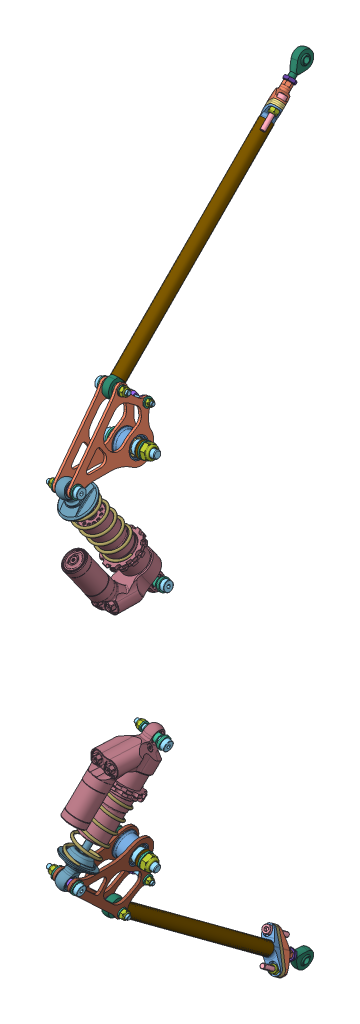
SolidWorks assembly PUTM-S-SR-DS, configuration Domyślna. Lengths in mm.
Overall size (128 1101.89 413.23).
117 component instances, 24 part files, 8 mates.
Components (placement in the parent):
- PUTM-S-SR-DS-Rocker-1: PUTM-S-SR-DS-Rocker [Domyślna] at origin size (72.21 637.68 125.56)
  - PUTM_S_SR_DS_Rockersleeve-1: PUTM_S_SR_DS_Rockersleeve [Domyślna] at (-1449.4181 239.4336 437.1843) x (0.986079 0.166257 -0.00253) z (0.063822 -0.364394 0.929055) size (24 33 33)
  - PUTM-S-SR-DS-Rockerplate-1: PUTM-S-SR-DS-Rockerplate [Domyślna] at (8.972 14.8477 31.7784) x (0.999705 0.009752 0.022243) z (-0.022218 -0.002628 0.99975) size (19.82 96.34 120.76)
  - PUTM-S-SR-DS-Rockerplate-2: PUTM-S-SR-DS-Rockerplate [Domyślna] at (-11.2426 11.4394 31.8303) x (0.999705 0.009752 0.022243) z (-0.022218 -0.002628 0.99975) size (19.82 96.34 120.76)
  - PUTM-S-SR-DS-NKIB 5901-1: PUTM-S-SR-DS-NKIB 5901 [Domyślna] at (-1457.4053 238.0869 437.2048) x (0.986079 0.166257 -0.00253) z (-0.069911 0.428358 0.900901) size (17.5 24 24)
  - PUTM-S-SR-DS-Seger-1: PUTM-S-SR-DS-Seger [24 mm] at (-1457.4053 238.0869 437.2048) x (0.038864 -0.215655 0.975696) z (-0.986079 -0.166257 0.00253) size (25.2 25.11 1.2)
  - PUTM-FT-ELESA_ISO7379-1: PUTM-FT-ELESA_ISO7379 [8-M6-25] at (-1479.6872 304.2624 449.2226) x (-0.986079 -0.166257 0.00253) z (0.161473 -0.961118 -0.224006) size (41.5 13 13)
  - PUTM-FT-FABORY_ISO7089-1: PUTM-FT-FABORY_ISO7089 [M8 [38093.080.001]] at (-1472.686 305.4428 449.2046) x (0.028434 -0.153611 0.987722) z (-0.986079 -0.166257 0.00253) size (16 16 1.6)
  - PUTM-FT-FABORY_ISO7089-2: PUTM-FT-FABORY_ISO7089 [M6 [38093.060.001]] at (-1447.4424 309.699 449.1398) x (0.032173 -0.175846 0.983892) z (-0.986079 -0.166257 0.00253) size (12 12 1.6)
  - PUTM-FT-FABORY_DIN985-1: PUTM-FT-FABORY_DIN985 [M6 [12348.060.001]] at (-1447.4424 309.699 449.1398) x (0.058443 -0.360799 -0.930811) z (0.986079 0.166257 -0.00253) size (11.9 10.35 6.18)
  - PUTM-FT-ELESA_ISO7379-2: PUTM-FT-ELESA_ISO7379 [6-M5-25] at (-1474.3165 277.9597 418.7611) x (-0.986079 -0.166257 0.00253) z (0.008863 -0.037361 0.999263) size (39 10 10)
  - PUTM-FT-FABORY_ISO7089-3: PUTM-FT-FABORY_ISO7089 [M6 [38093.060.001]] at (-1469.8791 278.7078 418.7497) x (0.116001 -0.676949 0.726831) z (0.986079 0.166257 -0.00253) size (12 12 1.6)
  - PUTM-FT-FABORY_ISO7089-4: PUTM-FT-FABORY_ISO7089 [M6 [38093.060.001]] at (-1443.0578 283.23 418.6809) x (0.028501 -0.15401 0.987658) z (-0.986079 -0.166257 0.00253) size (12 12 1.6)
  - PUTM-FT-FABORY_DIN985-2: PUTM-FT-FABORY_DIN985 [M5 [12348.050.001]] at (-1443.0578 283.23 418.6809) x (0.063056 -0.387983 -0.919507) z (0.986079 0.166257 -0.00253) size (9.51 8.27 5.13)
  - PUTM-FT-ELESA_ISO7379-3: PUTM-FT-ELESA_ISO7379 [8-M6-30] at (-1427.6768 235.7327 525.4287) x (0.986079 0.166257 -0.00253) z (0.154521 -0.921884 -0.355322) size (46.5 13 13)
  - PUTM-FT-FABORY_ISO7089-5: PUTM-FT-FABORY_ISO7089 [M8 [38093.080.001]] at (-1433.1002 234.8183 525.4426) x (0.058573 -0.36156 -0.930507) z (-0.986079 -0.166257 0.00253) size (16 16 1.6)
  - PUTM-FT-FABORY_ISO7089-6: PUTM-FT-FABORY_ISO7089 [M6 [38093.060.001]] at (-1461.4007 230.0467 525.5152) x (0.066136 -0.406128 -0.91142) z (-0.986079 -0.166257 0.00253) size (12 12 1.6)
  - PUTM-FT-FABORY_DIN985-3: PUTM-FT-FABORY_DIN985 [M6 [12348.060.001]] at (-1462.9785 229.7807 525.5193) x (-0.080848 0.492701 0.866435) z (-0.986079 -0.166257 0.00253) size (11.9 10.35 6.18)
  - PUTM-FT-ELESA_ISO7379-7: PUTM-FT-ELESA_ISO7379 [12-M10-45] at (-1479.9865 234.2796 437.2628) x (-0.986079 -0.166257 0.00253) z (0.136222 -0.816481 -0.561073) size (69 18 18)
  - PUTM-FT-FABORY_ISO7089-13: PUTM-FT-FABORY_ISO7089 [M12 [38093.120.001]] at (-1472.0979 235.6097 437.2425) x (0.070497 -0.431808 -0.899206) z (0.986079 0.166257 -0.00253) size (24 24 2.5)
  - PUTM-FT-FABORY_ISO7089-14: PUTM-FT-FABORY_ISO7089 [M10 [38093.100.001]] at (-1427.2313 243.1743 437.1274) x (0.028505 -0.154033 0.987654) z (-0.986079 -0.166257 0.00253) size (20 20 2)
  - PUTM-FT-FABORY_DIN985-7: PUTM-FT-FABORY_DIN985 [M10 [12348.100.001]] at (-1427.2313 243.1743 437.1274) x (0.063056 -0.387983 -0.919507) z (0.986079 0.166257 -0.00253) size (20.27 17.64 10.37)
  - PUTM-FT-FABORY_ISO7089-17: PUTM-FT-FABORY_ISO7089 [M8 [38093.080.001]] at (-1459.823 230.3127 525.5112) x (0.030102 -0.163528 0.986079) z (-0.986079 -0.166257 0.00253) size (16 16 1.6)
  - PUTM-S-Mush-1: PUTM-S-Mush [8x2] at (-1469.2348 306.0247 449.1958) x (0.986079 0.166257 -0.00253) z (-0.00325 0.034487 0.9994) size (2 12 12)
  - PUTM-S-Mush-2: PUTM-S-Mush [8x2] at (-1452.4714 308.8511 449.1527) x (-0.986079 -0.166257 0.00253) z (0.161903 -0.956569 0.24241) size (2 12 12)
  - PUTM-S-Mush-3: PUTM-S-Mush [6x4.5] at (-1464.8501 279.5557 418.7368) x (0.986079 0.166257 -0.00253) z (-0.012976 0.092116 0.995664) size (4.5 12 12)
  - PUTM-S-Mush-4: PUTM-S-Mush [6x4.5] at (-1448.0868 282.3821 418.6938) x (-0.986079 -0.166257 0.00253) z (0.038498 -0.243087 -0.96924) size (4.5 12 12)
  - PUTM-S-Mush-5: PUTM-S-Mush [6x5] at (-1456.3717 230.8946 525.5023) x (0.986079 0.166257 -0.00253) z (0.000139 0.014393 0.999896) size (4.5 12 12)
  - PUTM-S-Mush-6: PUTM-S-Mush [6x5] at (-1439.6084 233.721 525.4593) x (-0.986079 -0.166257 0.00253) z (0.038498 -0.243087 -0.96924) size (4.5 12 12)
  - PUTM-S-SR-Rocker-MushRocker-1: PUTM-S-SR-Rocker-MushRocker [Domyślna] at (-1432.2603 242.3264 437.1403) x (-0.986079 -0.166257 0.00253) z (0.11055 -0.666893 -0.736907) size (8 20 20)
  - PUTM-S-SR-Rocker-MushRocker_long-1: PUTM-S-SR-Rocker-MushRocker_long [Domyślna] at (-1466.7731 236.5075 437.2289) x (0.986079 0.166257 -0.00253) z (0.00253 0.000212 0.999997) size (9.5 20 20)
  - PUTM-FT-FABORY_ISO7089-7: PUTM-FT-FABORY_ISO7089 [M6 [38093.060.001]] at (-1449.0201 -309.433 449.1439) x (0.032173 0.175846 0.983892) z (0.986079 -0.166257 -0.00253) size (12 12 1.6)
  - PUTM-S-Mush-7: PUTM-S-Mush [6x4.5] at (-1448.0868 -282.3821 418.6938) x (-0.986079 0.166257 0.00253) z (-0.038498 -0.243087 0.96924) size (4.5 12 12)
  - PUTM-FT-FABORY_ISO7089-8: PUTM-FT-FABORY_ISO7089 [M6 [38093.060.001]] at (-1444.6355 -282.964 418.6849) x (0.028501 0.15401 0.987658) z (0.986079 -0.166257 -0.00253) size (12 12 1.6)
  - PUTM-FT-FABORY_ISO7089-9: PUTM-FT-FABORY_ISO7089 [M8 [38093.080.001]] at (-1434.678 -234.5523 525.4466) x (0.058573 0.36156 -0.930507) z (0.986079 -0.166257 -0.00253) size (16 16 1.6)
  - PUTM-S-Mush-8: PUTM-S-Mush [8x2] at (-1452.4714 -308.8511 449.1527) x (-0.986079 0.166257 0.00253) z (-0.161903 -0.956569 -0.24241) size (2 12 12)
  - PUTM-S-Mush-9: PUTM-S-Mush [8x2] at (-1469.2348 -306.0247 449.1958) x (0.986079 -0.166257 -0.00253) z (0.00325 0.034487 -0.9994) size (2 12 12)
  - PUTM-FT-FABORY_ISO7089-10: PUTM-FT-FABORY_ISO7089 [M6 [38093.060.001]] at (-1468.3014 -278.9738 418.7456) x (0.116001 0.676949 0.726831) z (-0.986079 0.166257 0.00253) size (12 12 1.6)
  - PUTM-S-Mush-10: PUTM-S-Mush [6x4.5] at (-1464.8501 -279.5557 418.7368) x (0.986079 -0.166257 -0.00253) z (0.012976 0.092116 -0.995664) size (4.5 12 12)
  - PUTM-S-Mush-11: PUTM-S-Mush [6x5] at (-1439.6084 -233.721 525.4593) x (-0.986079 0.166257 0.00253) z (-0.038498 -0.243087 0.96924) size (4.5 12 12)
  - PUTM-S-Mush-12: PUTM-S-Mush [6x5] at (-1456.3717 -230.8946 525.5023) x (0.986079 -0.166257 -0.00253) z (-0.000139 0.014393 -0.999896) size (4.5 12 12)
  - PUTM-FT-FABORY_DIN985-4: PUTM-FT-FABORY_DIN985 [M6 [12348.060.001]] at (-1462.9785 -229.7807 525.5193) x (0.080848 0.492701 -0.866435) z (-0.986079 0.166257 0.00253) size (11.9 10.35 6.18)
  - PUTM-FT-FABORY_ISO7089-11: PUTM-FT-FABORY_ISO7089 [M6 [38093.060.001]] at (-1462.9785 -229.7807 525.5193) x (0.066136 0.406128 -0.91142) z (0.986079 -0.166257 -0.00253) size (12 12 1.6)
  - PUTM-FT-FABORY_DIN985-5: PUTM-FT-FABORY_DIN985 [M5 [12348.050.001]] at (-1443.0578 -283.23 418.6809) x (-0.063056 -0.387983 0.919507) z (0.986079 -0.166257 -0.00253) size (9.51 8.27 5.13)
  - PUTM-FT-FABORY_DIN985-6: PUTM-FT-FABORY_DIN985 [M6 [12348.060.001]] at (-1447.4424 -309.699 449.1398) x (-0.058443 -0.360799 0.930811) z (0.986079 -0.166257 -0.00253) size (11.9 10.35 6.18)
  - PUTM-FT-ELESA_ISO7379-4: PUTM-FT-ELESA_ISO7379 [6-M5-25] at (-1474.3165 -277.9597 418.7611) x (-0.986079 0.166257 0.00253) z (-0.008863 -0.037361 -0.999263) size (39 10 10)
  - PUTM-FT-ELESA_ISO7379-5: PUTM-FT-ELESA_ISO7379 [8-M6-30] at (-1427.6768 -235.7327 525.4287) x (0.986079 -0.166257 -0.00253) z (-0.154521 -0.921884 0.355322) size (46.5 13 13)
  - PUTM-FT-FABORY_ISO7089-12: PUTM-FT-FABORY_ISO7089 [M8 [38093.080.001]] at (-1474.2638 -305.1768 449.2087) x (0.028434 0.153611 0.987722) z (0.986079 -0.166257 -0.00253) size (16 16 1.6)
  - PUTM-S-SR-DS-NKIB 5901-2: PUTM-S-SR-DS-NKIB 5901 [Domyślna] at (-1457.4053 -238.0869 437.2048) x (0.986079 -0.166257 -0.00253) z (0.069911 0.428358 -0.900901) size (17.5 24 24)
  - PUTM_S_SR_DS_Rockersleeve-2: PUTM_S_SR_DS_Rockersleeve [Domyślna] at (-1449.4181 -239.4336 437.1843) x (0.986079 -0.166257 -0.00253) z (-0.063822 -0.364394 -0.929055) size (24 33 33)
  - PUTM-S-SR-DS-Seger-2: PUTM-S-SR-DS-Seger [24 mm] at (-1458.5886 -237.8874 437.2079) x (0.038864 0.215655 0.975696) z (0.986079 -0.166257 -0.00253) size (25.2 25.11 1.2)
  - LustroPUTM-S-SR-DS-Rockerplate-3: LustroPUTM-S-SR-DS-Rockerplate [Domyślna] at (-11.2426 -11.4394 31.8303) x (0.999705 -0.009752 0.022243) z (0.022218 -0.002628 -0.99975) size (19.82 96.34 120.76)
  - PUTM-FT-ELESA_ISO7379-6: PUTM-FT-ELESA_ISO7379 [8-M6-25] at (-1479.6872 -304.2624 449.2226) x (-0.986079 0.166257 0.00253) z (-0.161473 -0.961118 0.224006) size (41.5 13 13)
  - LustroPUTM-S-SR-DS-Rockerplate-4: LustroPUTM-S-SR-DS-Rockerplate [Domyślna] at (8.972 -14.8477 31.7784) x (0.999705 -0.009752 0.022243) z (0.022218 -0.002628 -0.99975) size (19.82 96.34 120.76)
  - PUTM-FT-ELESA_ISO7379-8: PUTM-FT-ELESA_ISO7379 [12-M10-45] at (-1479.9865 -234.2796 437.2628) x (-0.986079 0.166257 0.00253) z (-0.136222 -0.816481 0.561073) size (69 18 18)
  - PUTM-FT-FABORY_ISO7089-15: PUTM-FT-FABORY_ISO7089 [M10 [38093.100.001]] at (-1429.2034 -242.8418 437.1325) x (0.028505 0.154033 0.987654) z (0.986079 -0.166257 -0.00253) size (20 20 2)
  - PUTM-FT-FABORY_DIN985-8: PUTM-FT-FABORY_DIN985 [M10 [12348.100.001]] at (-1427.2313 -243.1743 437.1274) x (-0.063056 -0.387983 0.919507) z (0.986079 -0.166257 -0.00253) size (20.27 17.64 10.37)
  - PUTM-FT-FABORY_ISO7089-16: PUTM-FT-FABORY_ISO7089 [M12 [38093.120.001]] at (-1469.6327 -236.0253 437.2362) x (0.070497 0.431808 -0.899206) z (-0.986079 0.166257 0.00253) size (24 24 2.5)
  - PUTM-S-SR-Rocker-MushRocker_long-2: PUTM-S-SR-Rocker-MushRocker_long [Domyślna] at (-1466.7731 -236.5075 437.2289) x (0.986079 -0.166257 -0.00253) z (-0.00253 0.000212 -0.999997) size (9.5 20 20)
  - PUTM-S-SR-Rocker-MushRocker-2: PUTM-S-SR-Rocker-MushRocker [Domyślna] at (-1432.2603 -242.3264 437.1403) x (-0.986079 0.166257 0.00253) z (-0.11055 -0.666893 0.736907) size (8 20 20)
  - PUTM-FT-FABORY_ISO7089-18: PUTM-FT-FABORY_ISO7089 [M8 [38093.080.001]] at (-1461.4007 -230.0467 525.5152) x (0.030102 0.163528 0.986079) z (0.986079 -0.166257 -0.00253) size (16 16 1.6)
- PUTM-S-SR-DS-Dampers-1: PUTM-S-SR-DS-Dampers [Domyślna] at origin size (85.35 513.33 145.32)
  - PUTM-S-SF-DS-Spring-1: PUTM-S-SF-DS-Spring [Domyślna] at (-1444.1735 -212.7911 512.9654) x (0.986637 -0.144478 0.075328) z (0.014827 0.540008 0.841529) size (39.96 93.9 39.96)
  - PUTM-S-SF-DS-Ohlines TTX25-Body-2: PUTM-S-SF-DS-Ohlines TTX25-Body [Default] at (-1439.9074 190.9912 498.9013) x (-0.983754 -0.17813 -0.022291) z (0.076805 -0.529861 0.8446) size (49.5 133.26 84.25)
  - PUTM-S-SF-DS-Ohlines TTX25-Head-2: PUTM-S-SF-DS-Ohlines TTX25-Head [Default] at (-1435.0737 166.2906 482.9658) x (-0.98031 -0.197286 0.008446) z (0.112538 -0.52303 0.844852) size (46 110.31 45.56)
  - PUTM-S-SF-DS-Spring-2: PUTM-S-SF-DS-Spring [Domyślna] at (-1430.6617 143.7448 468.4204) x (0.771486 0.444597 -0.455129) z (0.615208 -0.338845 0.711831) size (39.96 93.9 39.96)
  - PUTM-S-SF-DS-Ohlines TTX25-Body-4: PUTM-S-SF-DS-Ohlines TTX25-Body [Default] at (-1439.9074 -190.9912 498.9013) x (0.984775 -0.170339 0.034677) z (0.062367 0.532416 0.844182) size (49.5 133.26 84.25)
  - PUTM-S-SF-DS-Ohlines TTX25-Head-4: PUTM-S-SF-DS-Ohlines TTX25-Head [Default] at (-1435.0737 -166.2906 482.9658) x (0.984775 -0.170339 0.034677) z (0.062367 0.532416 0.844182) size (46 110.31 45.56)
  - PUTM-FT-ELESA_ISO7379-1: PUTM-FT-ELESA_ISO7379 [8-M6-30] at (-1399.0076 94.942 434.9254) x (0.983754 0.17813 0.022291) z (-0.160533 0.928479 -0.334898) size (46.5 13 13)
  - PUTM-FT-FABORY_ISO7089-1: PUTM-FT-FABORY_ISO7089 [M6 [38093.060.001]] at (-1434.7179 88.4759 434.1163) x (0.07174 -0.276262 -0.958401) z (0.983754 0.17813 0.022291) size (12 12 1.6)
  - PUTM-FT-FABORY_DIN985-1: PUTM-FT-FABORY_DIN985 [M6 [12348.060.001]] at (-1434.7179 88.4759 434.1163) x (0.128383 -0.611294 -0.780921) z (-0.983754 -0.17813 -0.022291) size (11.9 10.35 6.18)
  - PUTM-FT-FABORY_ISO7089-2: PUTM-FT-FABORY_ISO7089 [M8 [38093.080.001]] at (-1405.9923 93.6773 434.7672) x (0.05333 -0.171415 -0.983754) z (0.983754 0.17813 0.022291) size (16 16 1.6)
  - PUTM-FT-FABORY_ISO7089-3: PUTM-FT-FABORY_ISO7089 [M8 [38093.080.001]] at (-1407.5663 93.3923 434.7315) x (0.05333 -0.171415 -0.983754) z (0.983754 0.17813 0.022291) size (16 16 1.6)
  - PUTM-FT-ELESA_ISO7379-2: PUTM-FT-ELESA_ISO7379 [8-M6-30] at (-1399.0076 -94.942 434.9254) x (0.983754 -0.17813 0.022291) z (0.160533 0.928479 0.334898) size (46.5 13 13)
  - PUTM-FT-FABORY_DIN985-2: PUTM-FT-FABORY_DIN985 [M6 [12348.060.001]] at (-1434.7179 -88.4759 434.1163) x (-0.128383 -0.611294 0.780921) z (-0.983754 0.17813 -0.022291) size (11.9 10.35 6.18)
  - PUTM-FT-FABORY_ISO7089-4: PUTM-FT-FABORY_ISO7089 [M6 [38093.060.001]] at (-1433.1439 -88.7609 434.1519) x (0.07174 0.276262 -0.958401) z (-0.983754 0.17813 -0.022291) size (12 12 1.6)
  - PUTM-FT-FABORY_ISO7089-5: PUTM-FT-FABORY_ISO7089 [M8 [38093.080.001]] at (-1404.4183 -93.9623 434.8028) x (0.05333 0.171415 -0.983754) z (-0.983754 0.17813 -0.022291) size (16 16 1.6)
  - PUTM-FT-FABORY_ISO7089-6: PUTM-FT-FABORY_ISO7089 [M8 [38093.080.001]] at (-1405.9923 -93.6773 434.7672) x (0.05333 0.171415 -0.983754) z (-0.983754 0.17813 -0.022291) size (16 16 1.6)
- PUTM-S-SR-DS-Pushrod-1: PUTM-S-SR-DS-Pushrod [Domyślna] at origin size (67.25 1101.89 327.76)
  - PUTM-S-rodend-1: PUTM-S-rodend [8mm] at (-1491.4781 507.9515 188.691) x (0.99081 0.134634 -0.012991) z (-0.09835 0.783046 0.614138) size (12 54 24)
  - PUTM-S-Insert-M8-1: PUTM-S-Insert-M8 [M8] at (-1463.5158 324.8743 426.5985) x (-0.092745 0.607232 -0.789093) z (0.932105 -0.225718 -0.283251) size (38.3 16.51 15.5)
  - PUTM-S-DS-DIN-EN-ISO-4035-1: PUTM-S-DS-DIN-EN-ISO-4035 [M8_low] at (-1493.3001 519.8808 173.189) x (0.771125 0.545161 0.328885) z (0.092745 -0.607232 0.789093) size (13 15.01 4)
  - PUTM-S-rodend-2: PUTM-S-rodend [8mm] at (-1464.7409 332.8954 416.1752) x (-0.994345 -0.097577 0.041923) z (-0.05154 0.788519 0.612847) size (12 54 24)
  - PUTM-S-DS-DIN-EN-ISO-4035-2: PUTM-S-DS-DIN-EN-ISO-4035 [M8_low] at (-1463.0243 321.6559 430.7807) x (0.947463 0.297479 0.11756) z (0.092745 -0.607232 0.789093) size (13 15.01 4)
  - PUTM-S-SR-DS-1: PUTM-S-SR-DS [Domyślna] at (-1486.508 475.4108 230.9774) x (0.524771 0.703315 0.479544) z (0.092745 -0.607232 0.789093) size (16.7 16.7 291.95)
  - PUTM-S-SR-DS-Insert-shims-1: PUTM-S-SR-DS-Insert-shims [Domyślna] at (-1490.054 498.6277 200.8072) x (-0.632028 -0.64828 -0.424587) z (-0.769376 0.45935 0.443912) size (54 55.42 16.38)
  - PUTM-S-SR-DS-Insert-shims-2-1: PUTM-S-SR-DS-Insert-shims-2 [M6] at (-1490.6105 502.2711 196.0727) x (0.632028 0.64828 0.424587) z (-0.769376 0.45935 0.443912) size (54 25 19.71)
  - PUTM-S-SR-DS-Shims-1: PUTM-S-SR-DS-Shims [2mm] at (-1490.6105 502.2711 196.0727) x (0.632028 0.64828 0.424587) z (0.092745 -0.607232 0.789093) size (54 15.5 2)
  - PUTM-S-SR-DS-Shims-2: PUTM-S-SR-DS-Shims [2mm] at (-1490.2395 499.8421 199.2291) x (0.632028 0.64828 0.424587) z (0.092745 -0.607232 0.789093) size (54 15.5 2)
  - PUTM-S-SR-DS-Shims-3: PUTM-S-SR-DS-Shims [2mm] at (-1490.425 501.0566 197.6509) x (0.632028 0.64828 0.424587) z (0.092745 -0.607232 0.789093) size (54 15.5 2)
  - PUTM-FT-FABORY_ISO912-2: PUTM-FT-FABORY_ISO912 [M6x35 [07071.060.035]] at (-1501.9526 480.8042 198.6283) x (0.092745 -0.607232 0.789093) z (-0.995462 -0.039593 0.086533) size (41 10 10)
  - PUTM-FT-FABORY_ISO912-3: PUTM-FT-FABORY_ISO912 [M6x35 [07071.060.035]] at (-1478.7119 520.0945 198.2517) x (-0.092745 0.607232 -0.789093) z (0.50246 0.712742 0.489421) size (41 10 10)
  - PUTM-FT-FABORY_DIN985-1: PUTM-FT-FABORY_DIN985 [M6 [12348.060.001]] at (-1503.4365 490.5199 186.0028) x (-0.632028 -0.64828 -0.424587) z (-0.092745 0.607232 -0.789093) size (11.9 10.35 6.18)
  - PUTM-FT-FABORY_DIN985-2: PUTM-FT-FABORY_DIN985 [M6 [12348.060.001]] at (-1477.228 510.3788 210.8772) x (-0.350285 0.721949 0.596733) z (0.092745 -0.607232 0.789093) size (11.9 10.35 6.18)
  - PUTM-S-SR-DS-Shims-4: PUTM-S-SR-DS-Shims [2mm] at (-1490.2395 -499.8421 199.2291) x (0.632028 -0.64828 0.424587) z (-0.092745 -0.607232 -0.789093) size (54 15.5 2)
  - PUTM-S-SR-DS-Shims-5: PUTM-S-SR-DS-Shims [2mm] at (-1490.054 -498.6277 200.8072) x (0.632028 -0.64828 0.424587) z (-0.092745 -0.607232 -0.789093) size (54 15.5 2)
  - PUTM-S-SR-DS-Insert-shims-2-2: PUTM-S-SR-DS-Insert-shims-2 [M6] at (-1490.6105 -502.2711 196.0727) x (0.632028 -0.64828 0.424587) z (0.769376 0.45935 -0.443912) size (54 25 19.71)
  - PUTM-S-SR-DS-2: PUTM-S-SR-DS [Domyślna] at (-1464.1115 -328.7747 421.5299) x (0.524771 -0.703315 0.479544) z (-0.092745 -0.607232 -0.789093) size (16.7 16.7 291.95)
  - PUTM-FT-FABORY_DIN985-3: PUTM-FT-FABORY_DIN985 [M6 [12348.060.001]] at (-1503.4365 -490.5199 186.0028) x (0.632028 -0.64828 0.424587) z (-0.092745 -0.607232 -0.789093) size (11.9 10.35 6.18)
  - PUTM-FT-FABORY_ISO912-4: PUTM-FT-FABORY_ISO912 [M6x35 [07071.060.035]] at (-1478.7119 -520.0945 198.2517) x (-0.092745 -0.607232 -0.789093) z (-0.50246 0.712742 -0.489421) size (41 10 10)
  - PUTM-FT-FABORY_ISO912-5: PUTM-FT-FABORY_ISO912 [M6x35 [07071.060.035]] at (-1501.9526 -480.8042 198.6283) x (0.092745 0.607232 0.789093) z (0.995462 -0.039593 -0.086533) size (41 10 10)
  - PUTM-S-rodend-3: PUTM-S-rodend [8mm] at (-1464.7409 -332.8954 416.1752) x (-0.994345 0.097577 0.041923) z (0.05154 0.788519 -0.612847) size (12 54 24)
  - PUTM-S-DS-DIN-EN-ISO-4035-3: PUTM-S-DS-DIN-EN-ISO-4035 [M8_low] at (-1492.9291 -517.4518 176.3454) x (0.771125 -0.545161 0.328885) z (-0.092745 -0.607232 -0.789093) size (13 15.01 4)
  - PUTM-S-SR-DS-Shims-6: PUTM-S-SR-DS-Shims [2mm] at (-1490.425 -501.0566 197.6509) x (0.632028 -0.64828 0.424587) z (-0.092745 -0.607232 -0.789093) size (54 15.5 2)
  - PUTM-S-SR-DS-Insert-shims-2: PUTM-S-SR-DS-Insert-shims [Domyślna] at (-1490.054 -498.6277 200.8072) x (-0.632028 0.64828 -0.424587) z (0.769376 0.45935 -0.443912) size (54 55.42 16.38)
  - PUTM-FT-FABORY_DIN985-4: PUTM-FT-FABORY_DIN985 [M6 [12348.060.001]] at (-1477.228 -510.3788 210.8772) x (0.350285 0.721949 -0.596733) z (0.092745 0.607232 0.789093) size (11.9 10.35 6.18)
  - PUTM-S-DS-DIN-EN-ISO-4035-4: PUTM-S-DS-DIN-EN-ISO-4035 [M8_low] at (-1462.6533 -319.227 433.9371) x (0.947463 -0.297479 0.11756) z (-0.092745 -0.607232 -0.789093) size (13 15.01 4)
  - PUTM-S-rodend-4: PUTM-S-rodend [8mm] at (-1491.4781 -507.9515 188.691) x (0.99081 -0.134634 -0.012991) z (0.09835 0.783046 -0.614138) size (12 54 24)
  - PUTM-S-Insert-M8-2: PUTM-S-Insert-M8 [M8] at (-1463.5158 -324.8743 426.5985) x (-0.092745 -0.607232 -0.789093) z (-0.932105 -0.225718 0.283251) size (38.3 16.51 15.5)
- PUTM-S-SR-MushRocker-1: PUTM-S-SR-MushRocker [Domyślna] at (-1464.3079 236.9231 437.2225) x (0.986079 0.166257 -0.00253) z (0.002843 -0.001644 0.999995) size (7 20 20)
- PUTM-S-SR-MushRocker-2: PUTM-S-SR-MushRocker [Domyślna] at (-1433.2464 242.1602 437.1428) x (-0.986079 -0.166257 0.00253) z (0.012382 -0.088599 -0.99599) size (7 20 20)
- PUTM-S-SR-DS-DamperMush-1: PUTM-S-SR-DS-DamperMush [Domyślna] at (-1429.7007 89.3843 434.23) x (0.983754 0.17813 0.022291) z (-0.022291 -0.002002 0.99975) size (5.5 12 12)
- PUTM-S-SR-DS-DamperMush-2: PUTM-S-SR-DS-DamperMush [Domyślna] at (-1411.0094 92.7688 434.6535) x (-0.983754 -0.17813 -0.022291) z (0.044326 -0.120698 -0.991699) size (5.5 12 12)
- PUTM-S-SR-MushRocker-3: PUTM-S-SR-MushRocker [Domyślna] at (-1433.2464 -242.1602 437.1428) x (-0.986079 0.166257 0.00253) z (-0.012382 -0.088599 0.99599) size (7 20 20)
- PUTM-S-SR-MushRocker-4: PUTM-S-SR-MushRocker [Domyślna] at (-1464.3079 -236.9231 437.2225) x (0.986079 -0.166257 -0.00253) z (-0.002843 -0.001644 -0.999995) size (7 20 20)
- PUTM-S-SR-DS-DamperMush-3: PUTM-S-SR-DS-DamperMush [Domyślna] at (-1411.0094 -92.7688 434.6535) x (-0.983754 0.17813 -0.022291) z (-0.044326 -0.120698 0.991699) size (5.5 12 12)
- PUTM-S-SR-DS-DamperMush-4: PUTM-S-SR-DS-DamperMush [Domyślna] at (-1429.7007 -89.3843 434.23) x (0.983754 -0.17813 0.022291) z (0.022291 -0.002002 -0.99975) size (5.5 12 12)
Mates (geometry in assembly coordinates):
- Koncentryczne1: concentric anti-aligned: cylinder of PUTM-S-SR-DS-Rocker-1/PUTM-FT-ELESA_ISO7379-7 through (-1479.9865 234.2796 437.2628) axis (0.986079 0.166257 -0.00253) radius 6; cylinder of PUTM-S-SR-MushRocker-1 through (-1464.3079 236.9231 437.2225) axis (-0.986079 -0.166257 0.00253) radius 6
- Wspólnie1: coincident anti-aligned: plane of PUTM-S-SR-DS-Rocker-1/PUTM-S-SR-DS-NKIB 5901-1 through (-1458.6122 245.1924 433.7327) normal (-0.986079 -0.166257 0.00253); plane of PUTM-S-SR-MushRocker-1 through (-1458.7353 245.9755 437.2216) normal (0.986079 0.166257 -0.00253)
- Koncentryczne2: concentric aligned: cylinder of PUTM-S-SR-DS-Rocker-1/PUTM-FT-ELESA_ISO7379-7 through (-1479.9865 234.2796 437.2628) axis (0.986079 0.166257 -0.00253) radius 6; cylinder of PUTM-S-SR-MushRocker-2 through (-1433.2464 242.1602 437.1428) axis (0.986079 0.166257 -0.00253) radius 6
- Wspólnie2: coincident anti-aligned: plane of PUTM-S-SR-DS-Rocker-1/PUTM-S-SR-DS-NKIB 5901-1 through (-1441.0994 246.5919 434.4262) normal (0.986079 0.166257 -0.00253); plane of PUTM-S-SR-MushRocker-2 through (-1441.4754 248.8531 436.4452) normal (-0.986079 -0.166257 0.00253)
- Koncentryczne3: concentric aligned: cylinder of PUTM-S-SR-DS-Dampers-1/PUTM-FT-ELESA_ISO7379-1 through (-1399.0076 94.942 434.9254) axis (-0.983754 -0.17813 -0.022291) radius 4; cylinder of PUTM-S-SR-DS-DamperMush-1 through (-1429.7007 89.3843 434.23) axis (-0.983754 -0.17813 -0.022291) radius 4
- Wspólnie3: coincident anti-aligned: plane of PUTM-S-SR-DS-Dampers-1/PUTM-S-SF-DS-Ohlines TTX25-Body-2 through (-1423.4588 86.1158 431.6118) normal (-0.983754 -0.17813 -0.022291); plane of PUTM-S-SR-DS-DamperMush-1 through (-1425.1807 95.2841 434.3425) normal (0.983754 0.17813 0.022291)
- Koncentryczne4: concentric anti-aligned: cylinder of PUTM-S-SR-DS-Dampers-1/PUTM-FT-ELESA_ISO7379-1 through (-1399.0076 94.942 434.9254) axis (-0.983754 -0.17813 -0.022291) radius 4; cylinder of PUTM-S-SR-DS-DamperMush-2 through (-1411.0094 92.7688 434.6535) axis (0.983754 0.17813 0.022291) radius 4
- Wspólnie5: coincident anti-aligned: plane of PUTM-S-SR-DS-Dampers-1/PUTM-S-SF-DS-Ohlines TTX25-Body-2 through (-1415.5887 87.5409 431.7902) normal (0.983754 0.17813 0.022291); plane of PUTM-S-SR-DS-DamperMush-2 through (-1417.2899 96.672 433.8977) normal (-0.983754 -0.17813 -0.022291)
